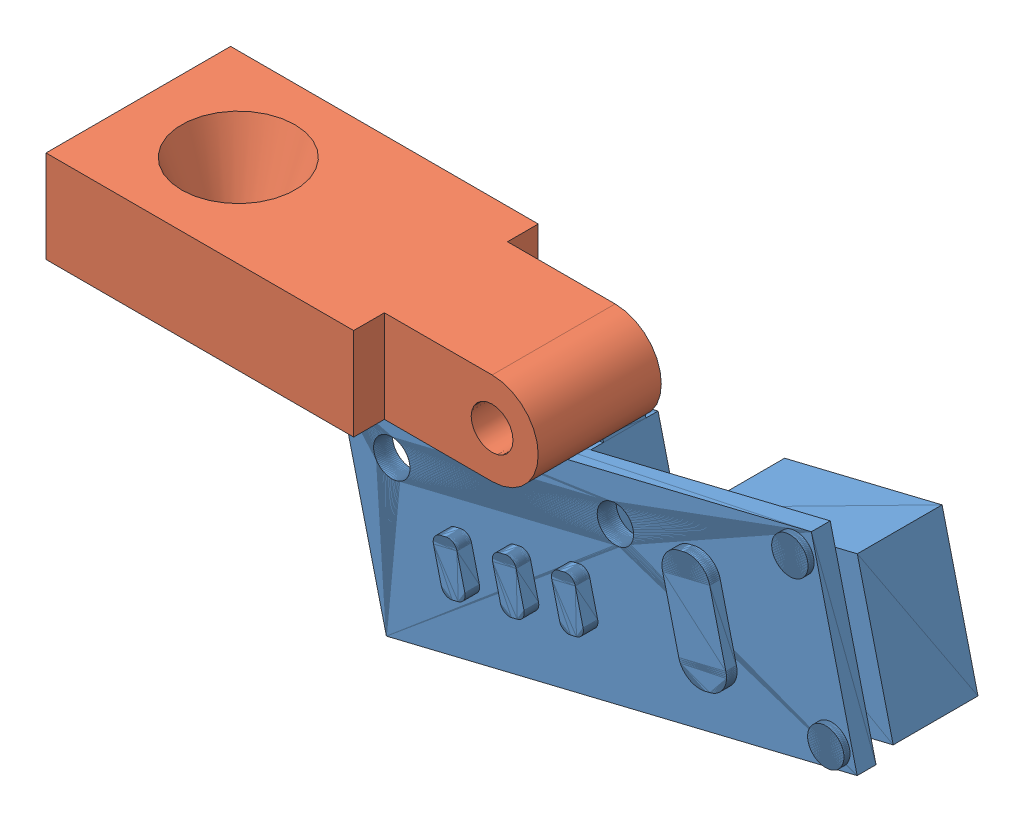
SolidWorks assembly limit_assembly, configuration Default. Lengths in mm.
Overall size (87.03 107.95 19.05).
3 component instances, 3 part files, 4 mates.
Components (placement in the parent):
- mechanical_endstop-1: mechanical_endstop [Default] at (58.8161 21.2263 -22.6708) x (0.971653 0.236413 0) z (0 0 -1) size (41.88 19.5 9.76)
- lever_bar-1: lever_bar [Default] at (59.5905 30.3176 -27.4208) size (38.1 7.62 15.24)
- limit_plate4-1: limit_plate4 [Default] at (83.7195 -31.9124 -33.7708) size (87.03 107.95 19.05)
Mates (geometry in assembly coordinates):
- Coincident10: coincident anti-aligned: plane of mechanical_endstop-1 through (58.8161 21.2263 -31.2308) normal (0 0 -1); plane of limit_plate4-1 through (83.7195 -31.9124 -31.2308) normal (0 0 1)
- Distance1: distance = 3.81 mm anti-aligned: plane of lever_bar-1 through (76.7355 30.3176 -27.4208) normal (0 0 -1); plane of limit_plate4-1 through (83.7195 -31.9124 -31.2308) normal (0 0 1)
- Coincident12: coincident aligned: plane of lever_bar-1 through (42.4455 34.1276 -17.2608) normal (0 1 0); plane of limit_plate4-1 through (42.3175 34.1276 -31.2308) normal (0 1 0)
- Distance2: distance = 0.254 mm anti-aligned: plane of mechanical_endstop-1 through (58.8161 26.2536 -22.6708) normal (0 1 0); plane of lever_bar-1 through (42.4455 26.5076 -17.2608) normal (0 -1 0)
